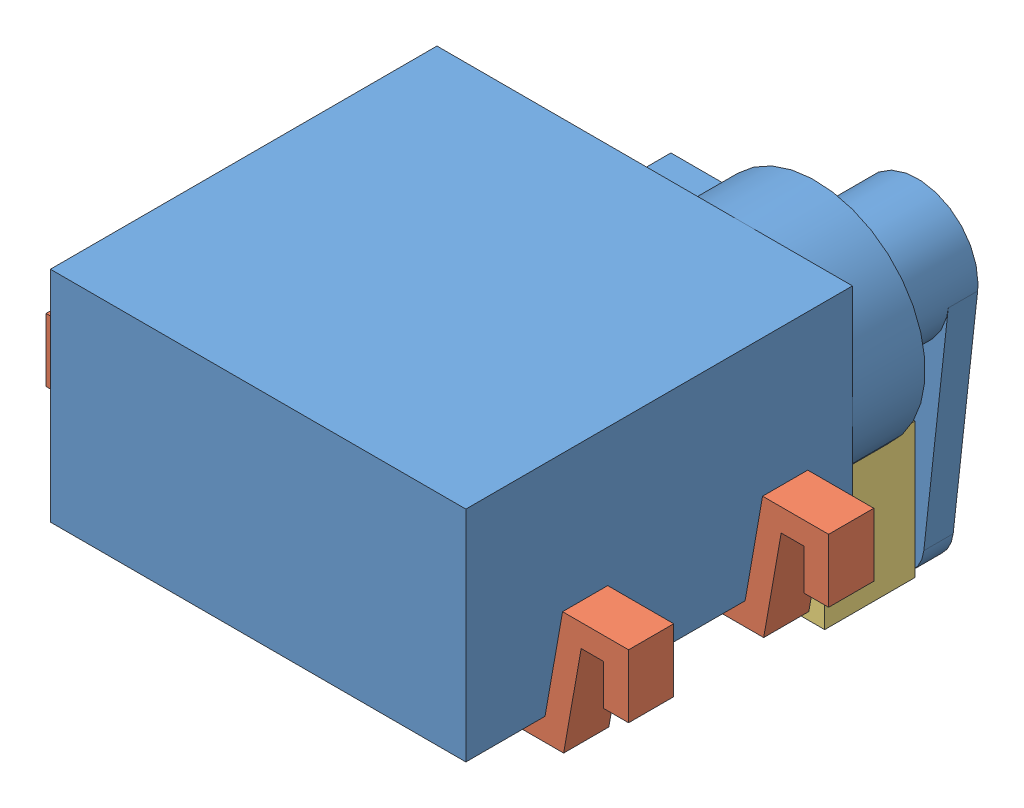
SolidWorks assembly Servo Assembly, configuration Default. Lengths in mm.
Overall size (32.77 20.85 31.55).
4 component instances, 3 part files, 7 mates.
Components (placement in the parent):
- Servo-1: Servo [Default] at (9.7036 12.6805 31.4945) size (23.37 20.85 31.55)
- Servo Strap-1: Servo Strap [Default] at (9.7036 11.4105 24.1226) x (1 0 0) z (0 -1 0) size (32.77 2.54 6.86)
- Servo Strap-2: Servo Strap [Default] at (9.7036 11.4105 37.9134) x (-1 0 0) z (0 -1 0) size (32.77 2.54 6.86)
- Servo Block-1: Servo Block [Default] at (15.2281 8.2101 17.5499) x (-1 0 0) z (0 -1 0) size (3.05 6.35 7.62)
Mates (geometry in assembly coordinates):
- Coincident1: coincident anti-aligned: plane of Servo-1 through (9.7036 12.6805 31.4945) normal (0 -1 0); plane of Servo Strap-1 through (-1.9804 12.6805 26.6626) normal (0 1 0)
- Coincident2: coincident anti-aligned: line of Servo-1 through (-1.9804 12.6805 20.6233) axis (0 0 1); line of Servo Strap-1 through (-1.9804 12.6805 26.6626) axis (0 0 -1)
- Coincident4: coincident anti-aligned: plane of Servo-1 through (9.7036 12.6805 31.4945) normal (0 -1 0); plane of Servo Strap-2 through (21.3876 12.6805 35.3734) normal (0 1 0)
- Coincident5: coincident anti-aligned: line of Servo-1 through (21.3876 12.6805 42.3657) axis (0 0 -1); line of Servo Strap-2 through (21.3876 12.6805 35.3734) axis (0 0 1)
- Concentric3: concentric: cylinder of Servo-1 through (15.2281 10.2421 13.5476) axis (0 0 -1) radius 0.381; cylinder of Servo Block-1 through (15.2281 10.2421 13.838) axis (0 0 1) radius 0.254
- Concentric4: concentric: cylinder of Servo-1 through (15.2281 6.1781 13.5476) axis (0 0 -1) radius 0.381; cylinder of Servo Block-1 through (15.2281 6.1781 13.838) axis (0 0 1) radius 0.254
- Coincident7: coincident anti-aligned: plane of Servo-1 through (15.2281 18.84 12.4699) normal (0 0 1); plane of Servo Block-1 through (15.2281 8.2101 12.4699) normal (0 0 -1)
